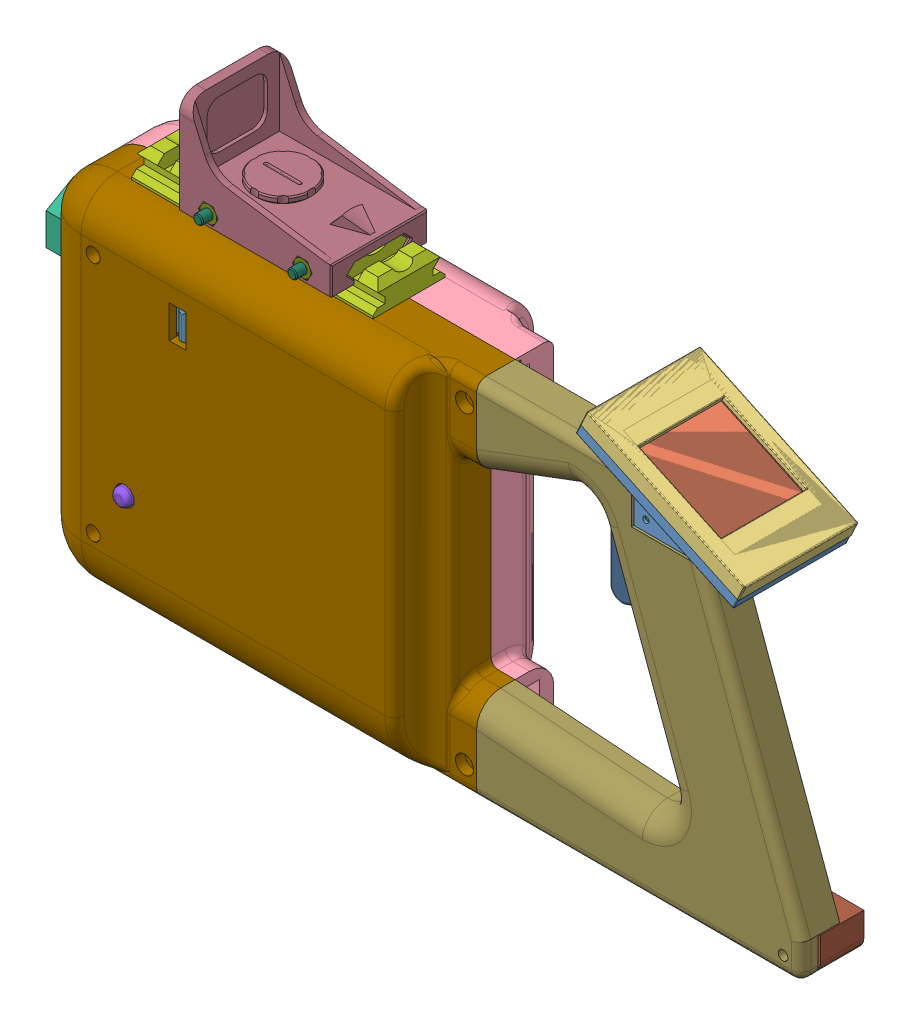
SolidWorks assembly TotalAssembly, configuration Default. Lengths in mm.
Overall size (317.61 196.22 65).
25 component instances, 16 part files, 53 mates.
Components (placement in the parent):
- DisplayGriffFlat-1: DisplayGriffFlat [Default] at (550.8815 131.717 -4.287) x (-1 0 0) z (0 0 -1) size (69.79 40.28 47.04)
  - Display_Holder_Single-1: Display_Holder_Single [Default] at (-65.8659 7.783 10.713) size (67.04 35.33 47)
  - Display_old-1: Display_old [Default] at (-70.0574 16.0854 26.673) x (-0.906308 -0.422618 0) z (-0.422618 0.906308 0) size (67.5 42.5 8)
  - DisplayLid-1: DisplayLid [Default] at (-72.3302 21.6459 26.673) x (0.906308 0.422618 0) z (0.422618 -0.906308 0) size (72 47 6.5)
- Korpus-1: Korpus [Standard] at (518.2703 72.0062 -60) x (0 1 0) z (0 0 1) size (150.84 170 30)
- Rohr-1: Rohr [Standard] at (420.2665 192.4359 -269.8973) x (0 -1 0) z (-1 0 0) size (32 23 140)
  - Rohr_u-2: Rohr_u [Standard] at (81.4359 239.8973 -75.0039) size (32 12.5 140)
  - Rohr_o-2: Rohr_o [Standard] at (81.4359 239.8973 -75.0039) x (-1 0 0) z (0 0 1) size (26.56 12.5 140)
- RailMount-1: RailMount [Standard] at (455.6777 150 -36.3922) x (-1 0 0) z (0 1 0) size (100 30 11.3)
- Button-1: Button [Standard] at (406.2703 50 -57) x (-0.330143 0.943931 0) z (-0.943931 -0.330143 0) size (11 7.5 11)
- Button-2: Button [Standard] at (406.2703 50 -3) x (0.821855 -0.569696 0) z (-0.569696 -0.821855 0) size (11 7.5 11)
- KorpusL-1: KorpusL [Standard] at (518.2703 72.0062 -60) x (0 1 0) z (0 0 1) size (150.84 170 32.5)
- Abzug-1: Abzug [Standard] at (601.6966 93.1353 -36.5) x (0.939723 0.341937 0) z (0 0 1) size (22.07 47 14)
- Griff_Akkuhalter-1: Griff_Akkuhalter [Standard] at (672.8754 -0.5 -40) size (75 15 18)
- Griff_L-1: Griff_L [Standard] at (538.2703 150 -30) x (-1 0 0) z (0 0 -1) size (144.61 150 16.57)
- RedDot-Sight-1: RedDot-Sight [Standard] at (419.0203 179.8199 -73.0762) x (0 0 -1) z (1 0 0) size (40 42 63)
- Display_old-1: Display_old [Default] at (620.676 147.925 -31) x (-0.906308 0.422618 0) z (0.422618 0.906308 0) size (67.5 42.5 8)
- DisplayLid-1: DisplayLid [Default] at (623.4746 153.2403 -31) x (0.906308 -0.422618 0) z (-0.422618 -0.906308 0) size (72 47 6.5)
- IR_Receiver-1: IR_Receiver [Standard] at (422.2203 116.6 -53) size (10 22 6.5)
- IR_Receiver-2: IR_Receiver [Standard] at (376.4703 60.0062 -26.05) x (0 0 -1) z (1 0 0) size (10 22 6.5)
- IR_Receiver-3: IR_Receiver [Standard] at (434.3203 116.6 -7) x (-1 0 0) z (0 0 -1) size (10 22 6.5)
- socket head cap screw_iso-1: socket head cap screw_iso [ISO 4762 M4 x 40 --- 20N] at (470.0203 158.6 -49.6) x (0 0 1) z (-1 0 0) size (44 7 7)
- socket head cap screw_iso-2: socket head cap screw_iso [ISO 4762 M4 x 40 --- 20N] at (431.0203 158.6 -49.6) x (0 0 1) z (-1 0 0) size (44 7 7)
- hex nut style 1 gradeab_iso-1: hex nut style 1 gradeab_iso [Hexagon Nut ISO - 4032 - M4 - W - N] at (470.0203 158.6 -10) x (-0.866025 0.5 0) z (0 0 1) size (7 8.08 3.2)
- hex nut style 1 gradeab_iso-2: hex nut style 1 gradeab_iso [Hexagon Nut ISO - 4032 - M4 - W - N] at (431.0203 158.6 -10) x (-0.866025 0.5 0) z (0 0 1) size (7 8.08 3.2)
Mates (geometry in assembly coordinates):
- Concentric1: concentric anti-aligned: cylinder of ? through (533.2703 139.5 -31) axis (0 0 -1) radius 2; cylinder of Korpus-1 through (533.2703 140 -60) axis (0 0 1) radius 2
- Coincident1: coincident anti-aligned: plane of ? through (528.2703 144.5 -36) normal (0 0 -1); plane of Korpus-1 through (527.2703 145.5 -36) normal (0 0 1)
- Parallel3: parallel anti-aligned: plane of ? through (528.2703 149.5 -31) normal (-1 0 0); plane of Korpus-1 through (527.2703 72.0062 -60) normal (1 0 0)
- Concentric7: concentric anti-aligned: circle of Korpus-1; circle of Rohr-1/Rohr_u-2
- Concentric8: concentric anti-aligned: circle of Korpus-1; circle of Rohr-1/Rohr_u-2
- Coincident11: coincident anti-aligned: plane of Korpus-1 through (518.2703 72.0062 -41.5) normal (0 0 1); plane of Rohr-1/Rohr_u-2 through (495.2703 111 -41.5) normal (0 0 -1)
- Parallel5: parallel anti-aligned: plane of Korpus-1 through (368.2703 150 -30) normal (0 1 0); plane of RailMount-1 through (455.6777 150 -36.3922) normal (0 -1 0)
- Concentric10: concentric aligned: circle of Korpus-1; circle of RailMount-1
- Concentric11: concentric anti-aligned: circle of Korpus-1; circle of RailMount-1
- Coincident12: coincident anti-aligned: plane of Korpus-1 through (368.2703 150 -30) normal (0 1 0); plane of RailMount-1 through (455.6777 150 -36.3922) normal (0 -1 0)
- Deckungsgleich2: coincident anti-aligned: plane of Korpus-1 through (368.2703 25 -57) normal (0 0 1); plane of Button-1 through (406.2703 50 -57) normal (0 0 -1)
- Konzentrisch1: concentric aligned: circle of Korpus-1; circle of Button-1
- Deckungsgleich4: coincident anti-aligned: plane of Button-2 through (406.2703 50 -3) normal (0 0 1); plane of KorpusL-1 through (368.2703 25 -3) normal (0 0 -1)
- Konzentrisch2: concentric anti-aligned: circle of Button-2; circle of KorpusL-1
- Deckungsgleich7: coincident anti-aligned: plane of ? through (592.8063 117.5681 -38.5) normal (0.939723 0.341937 0); plane of Abzug-1 through (601.6966 93.1353 -36.5) normal (-0.939723 -0.341937 0)
- Deckungsgleich8: coincident anti-aligned: plane of ? through (538.2703 149.5 -36.5) normal (0 0 1); plane of Abzug-1 through (601.6966 93.1353 -36.5) normal (0 0 -1)
- Konzentrisch5: concentric aligned: circle of ?; circle of Abzug-1
- Deckungsgleich9: coincident anti-aligned: plane of ? through (538.2703 149.5 -40) normal (0 0 1); plane of Griff_Akkuhalter-1 through (672.8754 -0.5 -40) normal (0 0 -1)
- Konzentrisch6: concentric aligned: circle of ?; circle of Griff_Akkuhalter-1
- Deckungsgleich11: coincident anti-aligned: plane of ? through (637.8754 4.5 -40) normal (0 1 0); plane of Griff_Akkuhalter-1 through (657.8754 4.5 -22) normal (0 -1 0)
- Deckungsgleich17: coincident anti-aligned: plane of Korpus-1 through (368.2703 0 -30) normal (0 0 1); plane of KorpusL-1 through (368.2703 0 -30) normal (0 0 -1)
- Deckungsgleich18: coincident aligned: plane of Korpus-1 through (368.2703 25 -35) normal (-1 0 0); plane of KorpusL-1 through (368.2703 25 -25) normal (-1 0 0)
- Deckungsgleich19: coincident aligned: plane of Korpus-1 through (368.2703 0 -35) normal (0 -1 0); plane of KorpusL-1 through (368.2703 0 -25) normal (0 -1 0)
- Deckungsgleich20: coincident aligned: plane of ? through (538.2703 149.5 -47) normal (0 1 0); plane of Griff_L-1 through (538.2703 149.5 -15) normal (0 1 0)
- Deckungsgleich21: coincident anti-aligned: plane of ? through (607.3791 39.5 -31) normal (0 0 1); plane of Griff_L-1 through (607.3791 39.5 -31) normal (0 0 -1)
- Deckungsgleich24: coincident aligned: plane of ? through (631.0304 129.5 -47) normal (0.939723 0.341937 0); plane of Griff_L-1 through (631.0304 129.5 -15) normal (0.939723 0.341937 0)
- Deckungsgleich26: coincident anti-aligned: plane of RailMount-1 through (520.5434 158.3284 -42.8284) normal (0 -0.707107 -0.707107); plane of RedDot-Sight-1 through (324.5399 155.6 -40.1) normal (0 0.707107 0.707107)
- Deckungsgleich27: coincident anti-aligned: plane of RailMount-1 through (520.5434 155.5 -20) normal (0 -0.707107 0.707107); plane of RedDot-Sight-1 through (324.5399 158.5698 -16.9302) normal (0 0.707107 -0.707107)
- Konzentrisch7: concentric aligned: circle of DisplayGriffFlat-1/Display_Holder_Single-1; circle of Display_old-1
- Konzentrisch8: concentric aligned: circle of DisplayGriffFlat-1/Display_Holder_Single-1; circle of Display_old-1
- Konzentrisch10: concentric anti-aligned: circle of Display_old-1; circle of DisplayLid-1
- Konzentrisch11: concentric anti-aligned: circle of Display_old-1; circle of DisplayLid-1
- Deckungsgleich29: coincident anti-aligned: plane of Display_old-1 through (622.3665 151.5502 -31) normal (0.422618 0.906308 0); plane of DisplayLid-1 through (622.6293 151.4277 -31) normal (-0.422618 -0.906308 0)
- Deckungsgleich31: coincident anti-aligned: plane of DisplayGriffFlat-1/Display_Holder_Single-1 through (620.4647 147.4718 -31) normal (0.422618 0.906308 0); plane of DisplayLid-1 through (620.7276 147.3493 -31) normal (-0.422618 -0.906308 0)
- Deckungsgleich32: coincident anti-aligned: plane of Korpus-1 through (368.2703 25 -57) normal (0 0 1); plane of IR_Receiver-1 through (432.2203 128.6 -57) normal (0 0 -1)
- Deckungsgleich33: coincident anti-aligned: plane of Korpus-1 through (422.2203 128.6 -57) normal (0 -1 0); plane of IR_Receiver-1 through (422.2203 128.6 -53) normal (0 1 0)
- Deckungsgleich34: coincident anti-aligned: plane of Korpus-1 through (422.2203 128.6 -57) normal (1 0 0); plane of IR_Receiver-1 through (422.2203 128.6 -53) normal (-1 0 0)
- Deckungsgleich35: coincident anti-aligned: plane of Korpus-1 through (518.2703 72.0062 -36.05) normal (0 0 1); plane of IR_Receiver-2 through (376.4703 72.0062 -36.05) normal (0 0 -1)
- Deckungsgleich36: coincident anti-aligned: plane of Korpus-1 through (376.4703 72.0062 -36.05) normal (-1 0 0); plane of IR_Receiver-2 through (376.4703 72.0062 -26.05) normal (1 0 0)
- Deckungsgleich37: coincident anti-aligned: plane of Korpus-1 through (371.2703 72.0062 -30) normal (0 -1 0); plane of IR_Receiver-2 through (376.4703 72.0062 -26.05) normal (0 1 0)
- Deckungsgleich38: coincident anti-aligned: plane of KorpusL-1 through (434.3203 128.6 -3) normal (-1 0 0); plane of IR_Receiver-3 through (434.3203 128.6 -7) normal (1 0 0)
- Deckungsgleich39: coincident anti-aligned: plane of KorpusL-1 through (422.2203 128.6 -3) normal (0 -1 0); plane of IR_Receiver-3 through (434.3203 128.6 -7) normal (0 1 0)
- Deckungsgleich40: coincident anti-aligned: plane of KorpusL-1 through (368.2703 25 -3) normal (0 0 -1); plane of IR_Receiver-3 through (434.3203 128.6 -3) normal (0 0 1)
- Deckungsgleich42: coincident anti-aligned: plane of KorpusL-1 through (368.2703 0 -25) normal (0 -1 0); plane of assembly through (0 0 0) normal (0 1 0)
- Tangential1: tangent anti-aligned: plane of RailMount-1 through (467.7703 155.5 -17.1716) normal (1 0 0); cylinder of RedDot-Sight-1 through (470.0203 158.6 -50) axis (0 0 -1) radius 2.25
- Konzentrisch181: concentric aligned: cylinder of RedDot-Sight-1 through (470.0203 158.6 -50) axis (0 0 -1) radius 2.25; cylinder of socket head cap screw_iso-1 through (470.0203 158.6 -81.35) axis (0 0 -1) radius 2
- Deckungsgleich491: coincident anti-aligned: plane of RedDot-Sight-1 through (470.0203 160.85 -45.6) normal (0 0 -1); plane of socket head cap screw_iso-1 through (470.0203 162.1 -45.6) normal (0 0 1)
- Konzentrisch19: concentric anti-aligned: cylinder of socket head cap screw_iso-1 through (470.0203 158.6 -81.35) axis (0 0 -1) radius 2; cylinder of hex nut style 1 gradeab_iso-1 through (470.0203 158.6 -35.0375) axis (0 0 1) radius 2
- Deckungsgleich50: coincident anti-aligned: plane of RedDot-Sight-1 through (419.0203 179.8199 -13.2) normal (0 0 1); plane of hex nut style 1 gradeab_iso-1 through (467.9996 155.1 -13.2) normal (0 0 -1)
- Deckungsgleich51: coincident anti-aligned: plane of RedDot-Sight-1 through (472.0411 162.1 -13.2) normal (0 -1 0); plane of hex nut style 1 gradeab_iso-1 through (472.0411 162.1 -13.2) normal (0 1 0)
- Deckungsgleich56: coincident aligned: plane of KorpusL-1 through (368.2703 25 0) normal (0 0 1); plane of assembly through (0 0 0) normal (0 0 1)
- Konzentrisch182: concentric anti-aligned: circle of Korpus-1; circle of Griff_L-1
- Deckungsgleich493: coincident aligned: plane of KorpusL-1 through (538.2703 150 -14) normal (0 0 1); plane of Griff_L-1 through (607.3791 40 -14) normal (0 0 1)
